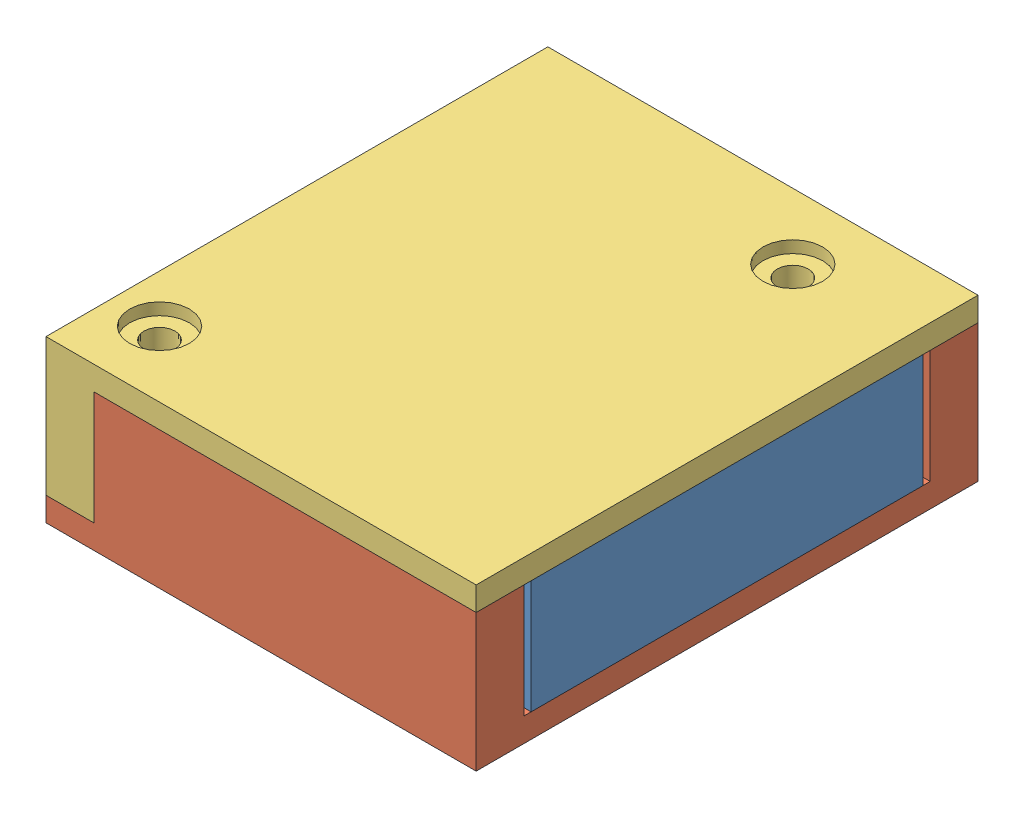
SolidWorks assembly 装配体, configuration Default. Lengths in mm.
Overall size (36 13.5 42).
3 component instances, 3 part files, 8 mates.
Components (placement in the parent):
- hslink-1: hslink [默认] at (-11.7975 1.7381 34.0321) size (34 9.5 35)
- 下壳-1: 下壳 [默认] at (-11.7975 -2.2119 34.0321) x (-1 0 0) z (0 -1 0) size (36 42 11.5)
- 上盖-1: 上盖 [默认] at (-11.7975 7.2881 34.0321) x (1 0 0) z (0 1 0) size (36 42 12.5)
Mates (geometry in assembly coordinates):
- 在位1: in place: plane of hslink-1 through (9.2025 -1.7119 50.4321) normal (0 -1 0); plane of ? through (0 -1.7119 0) normal (0 -1 0); moOrthogonalPlaneRef_w of hslink-1 through (9.2025 -1.7119 50.4321) normal (0 -1 0); plane of ? through (0 -1.7119 0) normal (0 0 -1); plane of hslink-1 through (9.2025 -1.7119 50.4321) normal (0 -1 0); plane of ? through (0 -1.7119 0) normal (-1 0 0); plane of hslink-1 through (9.2025 -2.2119 50.4321) normal (0 -1 0); unknown of 下壳-1
- 重合1: coincident aligned: plane of ?; plane of ?
- 重合2: coincident aligned: moOrthogonalPlaneRef_w of hslink-1 through (-11.7975 -2.2119 34.0321) normal (0 0 -1); plane of 零件2^装配体-1 through (-11.7975 -2.2119 34.0321) normal (0 0 -1)
- 重合3: coincident anti-aligned: moOrthogonalPlaneRef_w of hslink-1 through (-11.7975 -2.2119 34.0321) normal (1 0 0); plane of 零件2^装配体-1 through (-11.7975 -2.2119 34.0321) normal (-1 0 0)
- 在位3: in place: plane of ? through (-11.7975 6.7881 34.0321) normal (0 1 0); plane of ? through (0 6.7881 0) normal (0 1 0); plane of ? through (-11.7975 6.7881 34.0321) normal (0 1 0); plane of ? through (0 6.7881 0) normal (0 0 -1); plane of ? through (-11.7975 6.7881 34.0321) normal (0 1 0); plane of ? through (0 6.7881 0) normal (1 0 0); plane of 下壳-1 through (-11.7975 7.2881 34.0321) normal (0 1 0); unknown of 上盖-1
- 重合7: coincident aligned: plane of ?; plane of ?
- 重合8: coincident aligned: moOrthogonalPlaneRef_w of 下壳-1 through (-11.7975 7.2881 34.0321) normal (0 0 -1); plane of 上盖-1 through (-11.7975 7.2881 34.0321) normal (0 0 -1)
- 重合9: coincident anti-aligned: moOrthogonalPlaneRef_w of 下壳-1 through (-11.7975 7.2881 34.0321) normal (-1 0 0); plane of 上盖-1 through (-11.7975 7.2881 34.0321) normal (1 0 0)
